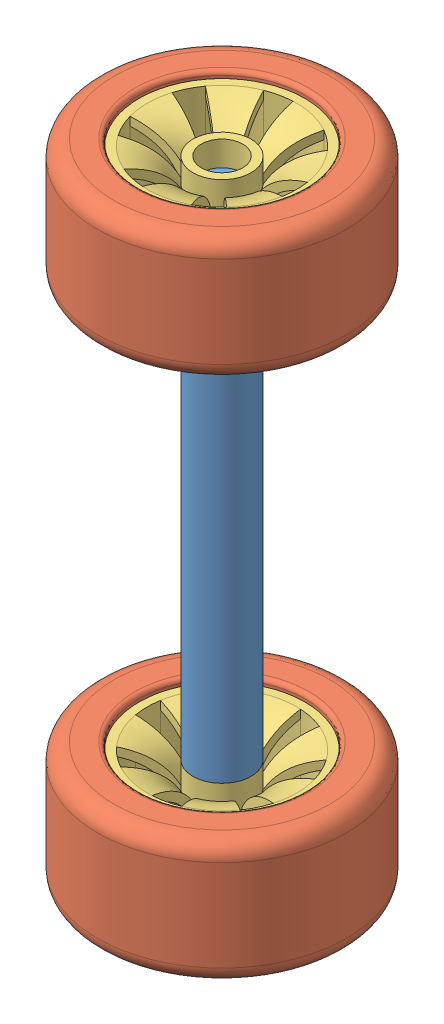
SolidWorks assembly wheels with axial, configuration Default. Lengths in mm.
Overall size (40.2 78 40.2).
7 component instances, 3 part files, 2 mates.
Components (placement in the parent):
- axial-1: axial [Default] at (39.9144 12.7845 62.5889) size (7.03 70 7.03)
- wheel complete-1: wheel complete [Default] at (39.9144 77.6193 62.5889) x (-0.44385 0 0.896101) z (0 -1 0) size (30 30 15)
  - wheel tire-1: wheel tire [Default] at origin size (30 30 15)
  - wheel for robot-2: wheel for robot [Default] at (0 0 7.8348) x (0 0 -1) z (1 0 0) size (14 22 22)
- wheel complete-2: wheel complete [Default] at (39.9144 14.6193 62.5889) x (-0.975761 0 -0.218838) z (0 -1 0) size (30 30 15)
  - wheel tire-1: wheel tire [Default] at origin size (30 30 15)
  - wheel for robot-2: wheel for robot [Default] at (0 0 7.8348) x (0 0 -1) z (1 0 0) size (14 22 22)
Mates (geometry in assembly coordinates):
- Coincident4: coincident aligned: circle of axial-1; circle of wheel complete-1/wheel for robot-2
- Coincident5: coincident anti-aligned: circle of axial-1; circle of wheel complete-2/wheel for robot-2
